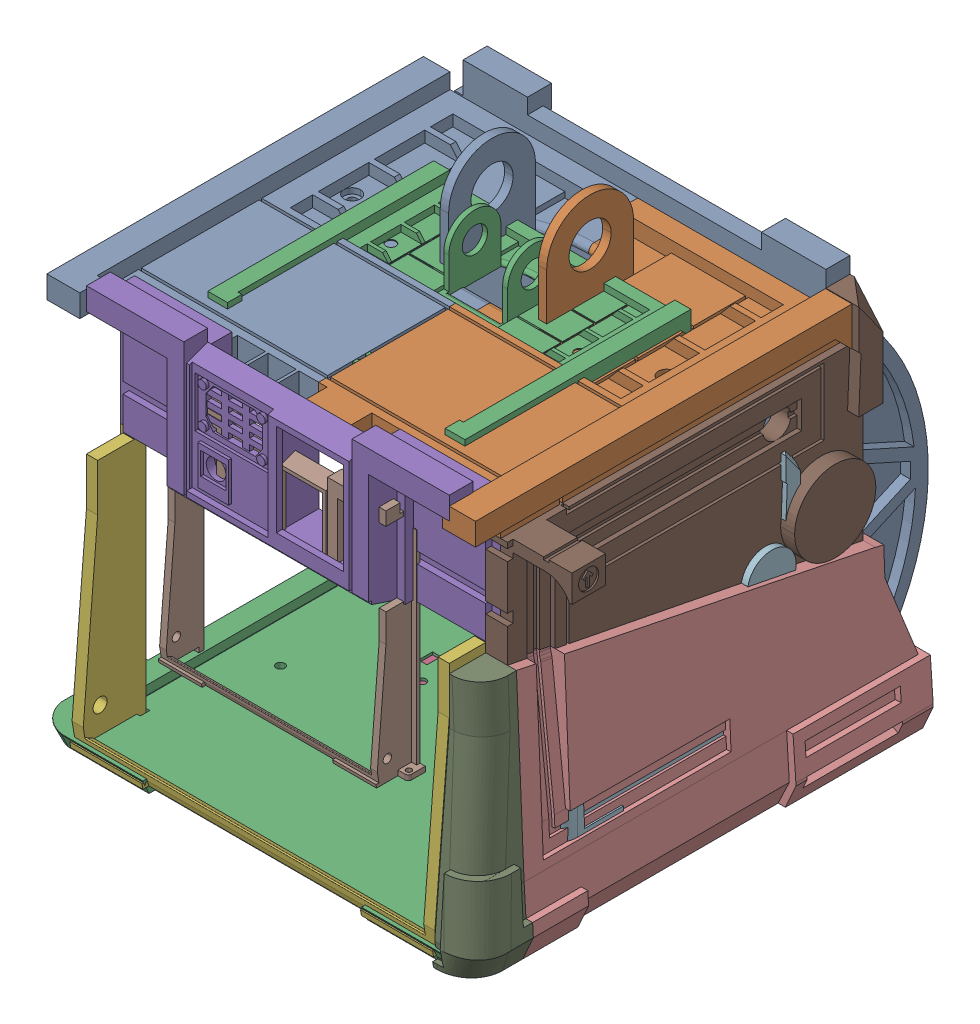
SolidWorks assembly Assem2, configuration Default. Lengths in mm.
Overall size (287.31 276.33 303.83).
5 component instances, 5 part files, 5 mates.
Components (placement in the parent):
- body-back-1: body-back [Default] at (50.8097 -29.6664 -2.6363) size (236.5 238.33 67.27)
- body-bottom-1: body-bottom [Default] at (-94.9404 -69.2633 191.1436) size (260 8.33 268.83)
- body-front-1: body-front [Default] at (-85.3157 -16.2837 211.729) size (236.5 238.33 38.58)
- body-left-1: body-left [Default] at (94.9867 -42.8798 171.9207) size (47.92 238.33 272.05)
- body-top-1: body-top [Default] at (-97.4578 135.7713 190.2687) size (255 61.67 224)
Mates (geometry in assembly coordinates):
- Coincident1: coincident aligned: circle of body-back-1; circle of body-bottom-1
- Coincident2: coincident aligned: circle of body-bottom-1; circle of body-left-1
- Coincident3: coincident aligned: circle of body-front-1; circle of body-left-1
- Coincident4: coincident anti-aligned: plane of body-left-1 through (90.9763 137.6024 213.3619) normal (0 1 0); plane of body-top-1 through (-148.4188 137.6024 235.0285) normal (0 -1 0)
- Coincident5: coincident anti-aligned: plane of body-left-1 through (103.8929 -77.3976 11.0285) normal (0 0 1); plane of body-top-1 through (-148.4188 146.4358 11.0285) normal (0 0 -1)
